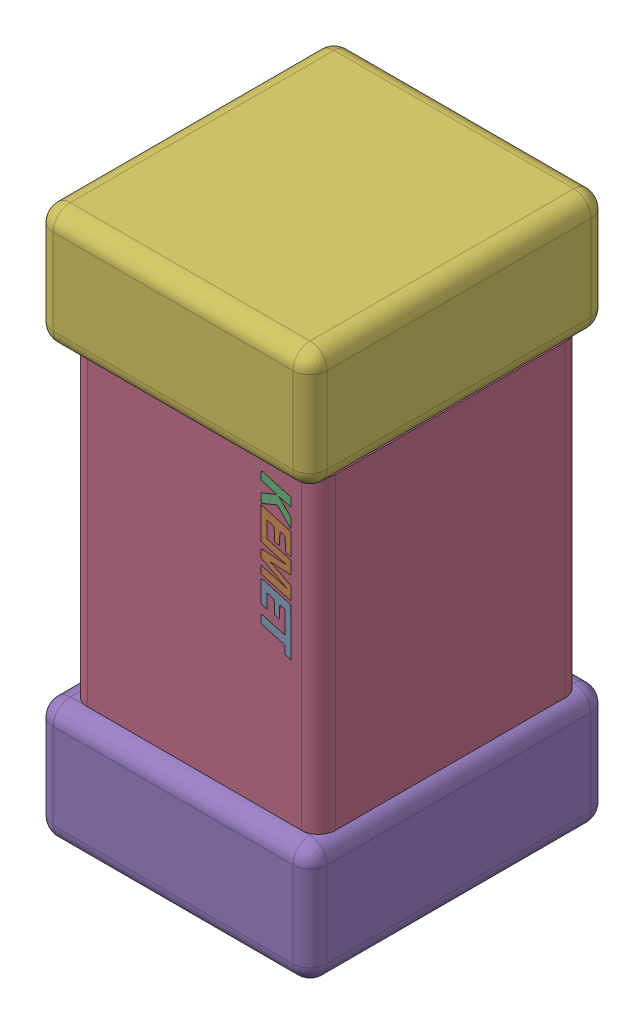
SolidWorks assembly C2.step, configuration Default. Lengths in mm.
Overall size (0.8 1.6 0.87).
3 component instances, 3 part files, 0 mates.
Components (placement in the parent):
- Cap_KEMET_C0603C272M5JACTU_eec.step-1: Cap_KEMET_C0603C272M5JACTU_eec.step [Default] at (53.467 55.626 0) x (0 -1 0) z (0 0 1) size (0.44 0.09 0)
- Cap_KEMET_C0603C272M5JACTU_eec-9.step-1: Cap_KEMET_C0603C272M5JACTU_eec-9.step [Default] at (53.467 55.626 0) x (0 -1 0) z (0 0 1) size (0.9 0.72 0.77)
- Cap_KEMET_C0603C272M5JACTU_eec-10.step-1: Cap_KEMET_C0603C272M5JACTU_eec-10.step [Default] at (53.467 55.626 0) x (0 -1 0) z (0 0 1) size (1.6 0.8 0.87)
